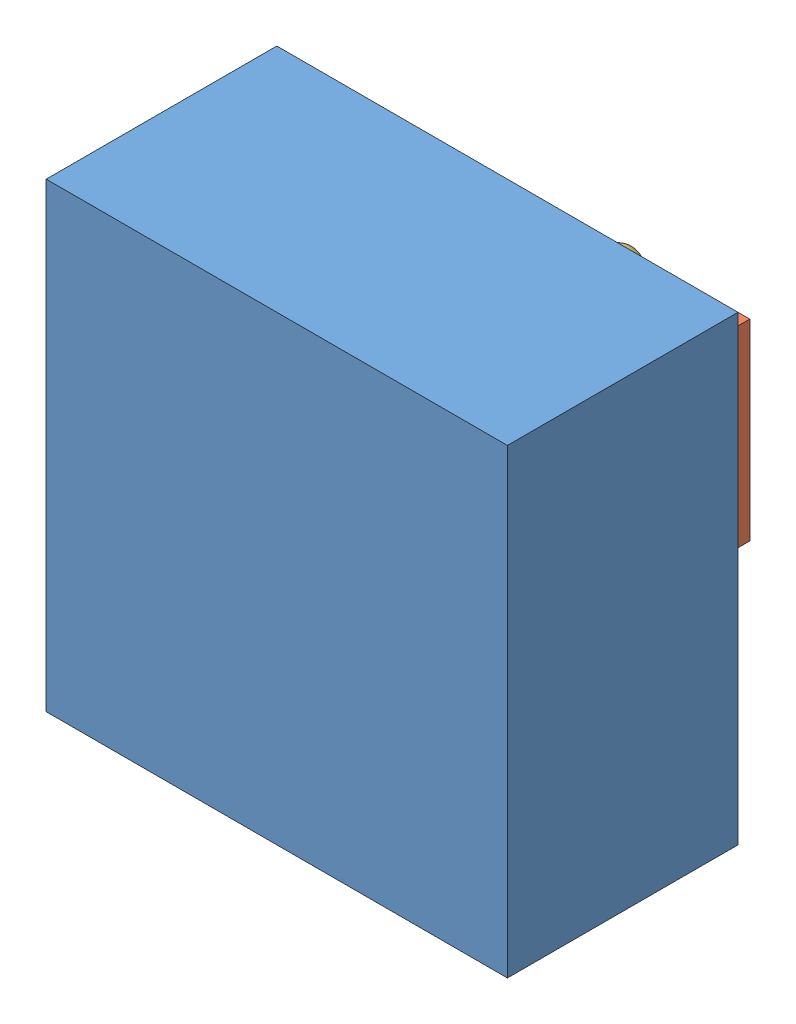
SolidWorks assembly peg hole 1, configuration Default. Lengths in mm.
Overall size (120 120 100).
4 component instances, 3 part files, 2 mates.
Components (placement in the parent):
- cubehole-1: cubehole [默认] at (39.9362 66.0398 73.4279) size (120 120 60)
- cube peg-1: cube peg [默认] at (50.358 44.4564 33.4279) x (0 -1 0) z (0 0 1) size (50 50 90)
- ballsensor-1: ballsensor [Default] at (49.4148 79.7804 44.4918) x (0.059149 -0.318675 0.946017) z (0.981646 0.190691 0.00286) size (10 10 10)
- ballsensor-2: ballsensor [Default] at (56.3893 19.7804 43.3917) x (-0.098927 0.304365 0.947405) z (0.89001 0.4529 -0.052565) size (10 10 10)
Mates (geometry in assembly coordinates):
- 相切1: tangent anti-aligned: plane of cube peg-1 through (72.696 24.7804 123.4279) normal (0 -1 0); sphere of ballsensor-2
- 相切3: tangent anti-aligned: plane of cube peg-1 through (72.696 74.7804 123.4279) normal (0 1 0); sphere of ballsensor-1
